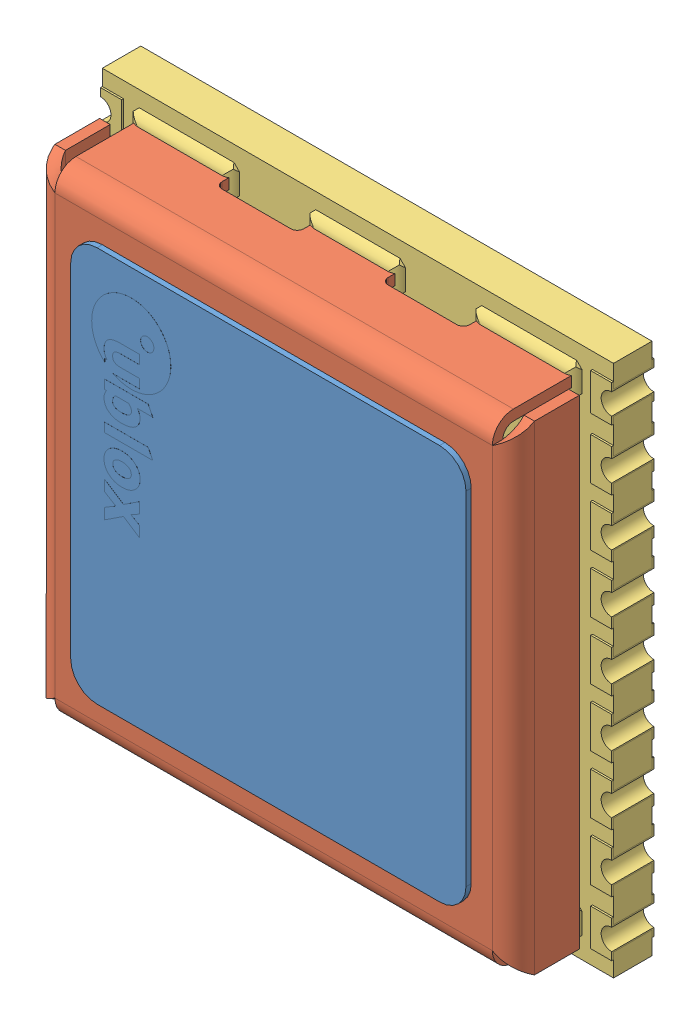
SolidWorks assembly MAX, configuration Default. Lengths in mm.
Overall size (9.7 10.1 2.47).
3 component instances, 3 part files, 0 mates.
Components (placement in the parent):
- u-blox_MAX_label_Default-1: u-blox_MAX_label_Default [Default] at (-0.1524 0.0561 1.965) x (0 -1 0) z (-1 0 0) size (7.5 0.11 7.5)
- Shield-1: Shield [Default] at (3.9976 4.2061 1.965) x (-1 0 0) z (0 1 0) size (9.1 1.5 9.13)
- MAX_PCB-1: MAX_PCB [Default] at (-0.1524 0.0561 -0.365) size (9.7 10.1 0.9)
